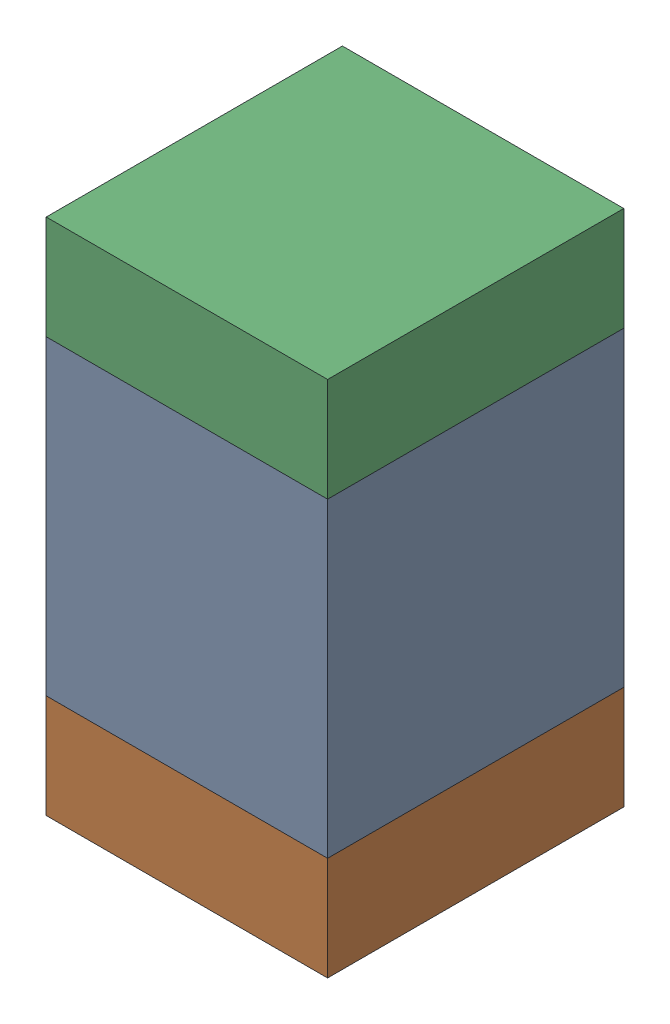
SolidWorks assembly C4-1, configuration Default. Lengths in mm.
Overall size (0.95 1.75 1).
6 component instances, 2 part files, 0 mates.
Components (placement in the parent):
- 959208528-1-1: 959208528-1 [Default] at (127.791 83.885 0) size (0.95 1.05 1)
  - Extruded-46-1: Extruded-46 [Default] at origin size (0.95 1.05 1)
- 959208664-1-1: 959208664-1 [Default] at (127.791 83.185 0) size (0.95 0.35 1)
  - Extruded-45-1: Extruded-45 [Default] at origin size (0.95 0.35 1)
- 959208664-1-2: 959208664-1 [Default] at (127.791 84.585 0) size (0.95 0.35 1)
  - Extruded-45-1: Extruded-45 [Default] at origin size (0.95 0.35 1)
